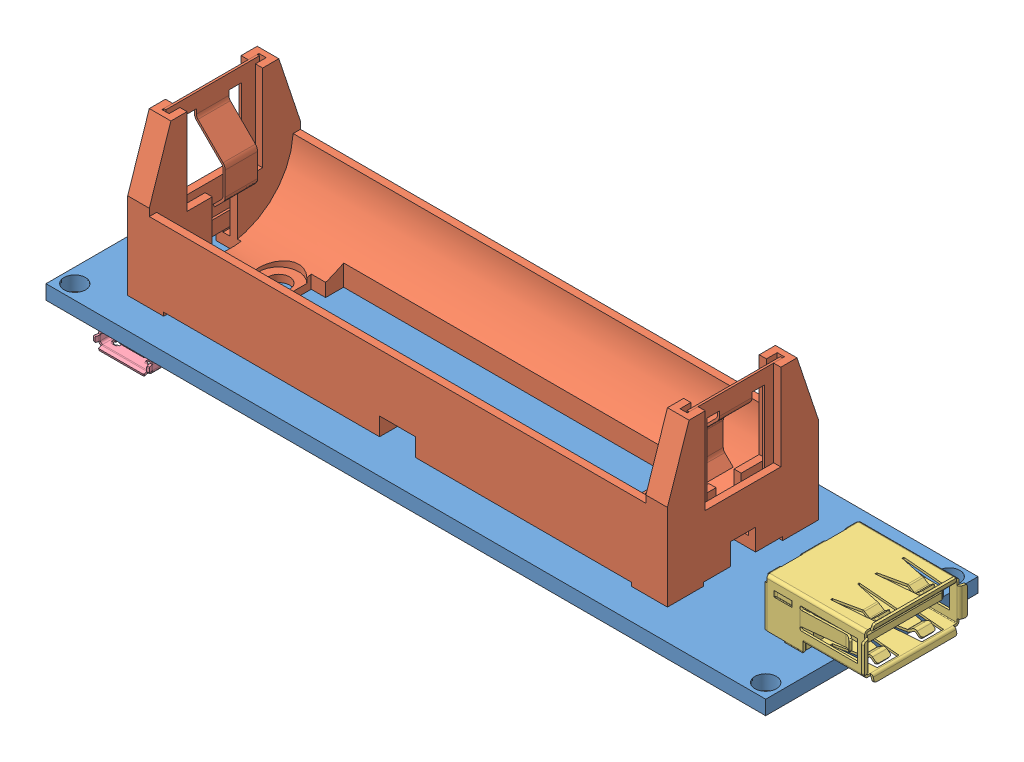
SolidWorks assembly bat_shield, configuration Default. Lengths in mm.
Overall size (106.11 25.64 29.5).
4 component instances, 4 part files, 10 mates.
Components (placement in the parent):
- wemos_board-1: wemos_board [Default] at (-11.1526 -8.39 7.9122) size (100 2 29.5)
- battery_holder-1: battery_holder [Default] at (-6.5793 -6.39 5.643) size (75 21 21)
- usb-1: usb [Default] at (49.6257 -8.09 -16.112) x (0 0 1) z (-1 0 0) size (15.78 11.14 14.45)
- MicroUSB_Pinboard_5_Pins-2: MicroUSB_Pinboard_5_Pins [Standard] at (-41.6369 7.11 12.643) x (0 0 1) z (0 -1 0) size (11.21 7.77 3.44)
Mates (geometry in assembly coordinates):
- Coincident1: coincident anti-aligned: plane of wemos_board-1 through (-11.1526 -6.39 7.9122) normal (0 1 0); plane of battery_holder-1 through (-6.5793 -6.39 5.643) normal (0 -1 0)
- Distance2: distance = 4.25 mm aligned: plane of battery_holder-1 through (-44.0793 14.61 16.143) normal (0 0 1); plane of wemos_board-1 through (-51.1793 -6.39 20.393) normal (0 0 1)
- Coincident4: coincident anti-aligned: plane of wemos_board-1 through (-11.1526 -6.39 7.9122) normal (0 1 0); plane of usb-1 through (44.8557 -6.39 5.643) normal (0 -1 0)
- Coincident5: coincident aligned: plane of wemos_board-1 through (48.8207 -6.39 -9.107) normal (1 0 0); plane of usb-1 through (48.8207 -5.79 5.643) normal (1 0 0)
- Distance3: distance = 8.195 mm aligned: plane of usb-1 through (54.3757 -4.885 12.198) normal (0 0 1); plane of wemos_board-1 through (-51.1793 -6.39 20.393) normal (0 0 1)
- Distance4: distance = 7.1 mm aligned: plane of battery_holder-1 through (-44.0793 14.61 16.143) normal (-1 0 0); plane of wemos_board-1 through (-51.1793 -6.39 -9.107) normal (-1 0 0)
- Coincident8: coincident: plane of wemos_board-1 through (-11.1526 -8.39 7.9122) normal (0 -1 0); plane of MicroUSB_Pinboard_5_Pins-2 through (-34.5793 -8.39 19.643) normal (0 -1 0)
- Parallel1: parallel: plane of wemos_board-1 through (-51.1793 -6.39 20.393) normal (0 0 1); plane of MicroUSB_Pinboard_5_Pins-2 through (-34.5793 -8.39 19.643) normal (0 0 1)
- Distance5: distance = 6.5 mm: plane of MicroUSB_Pinboard_5_Pins-2 through (-44.6793 -14.0497 17.119) normal (-1 0 0); plane of wemos_board-1 through (-51.1793 -6.39 -9.107) normal (-1 0 0)
- Distance6: distance = 0.75 mm aligned: plane of MicroUSB_Pinboard_5_Pins-2 through (-34.5793 -8.39 19.643) normal (0 0 1); plane of wemos_board-1 through (-51.1793 -6.39 20.393) normal (0 0 1)
